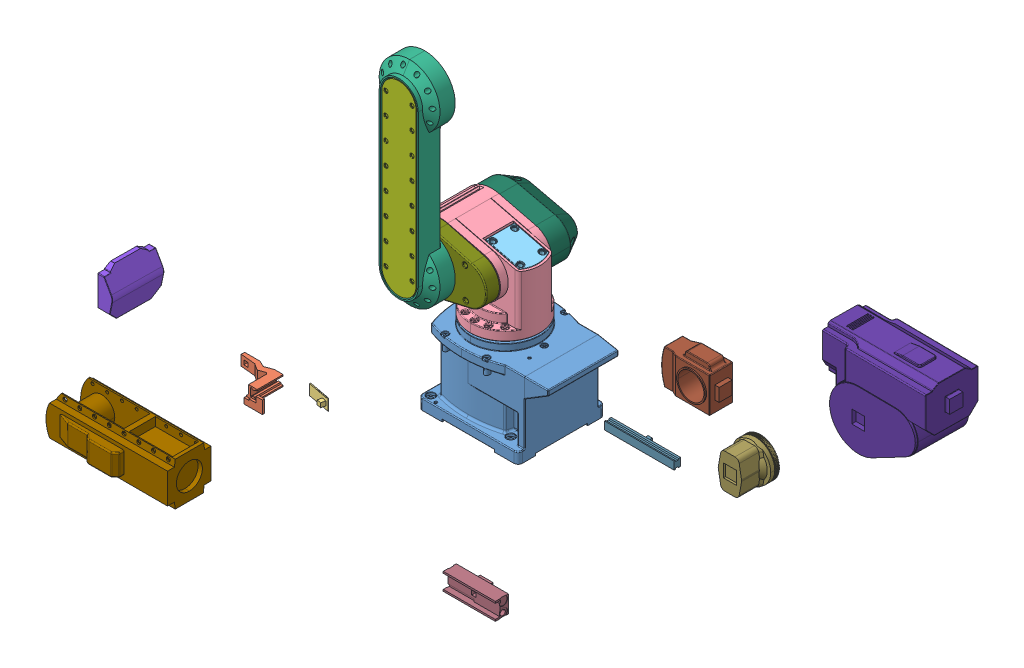
SolidWorks assembly Movable Step asembly, configuration Default. Lengths in mm.
Overall size (1391.39 998.07 787.43).
17 component instances, 17 part files, 19 mates.
Components (placement in the parent):
- Base.step-1: Base.step [Default] at (50.8691 16.3662 238.0648) size (280 185 200)
- Gripper_left^industry_robot_arm_3.step-1: Gripper_left^industry_robot_arm_3.step [Default] at (673.7931 -125.95 576.646) size (105.79 39 65)
- Gripper_right_grip^industry_robot_arm_3.step-1: Gripper_right_grip^industry_robot_arm_3.step [Default] at (-1508.2384 -488.0095 2246.7024) size (52.87 24 20.92)
- Joint_1.step-1: Joint_1.step [Default] at (68.6257 327.9173 238.0648) size (242.75 189 160)
- Joint_1_top_cap.step-1: Joint_1_top_cap.step [Default] at (70.9238 311.3662 238.0648) x (1 0 0) z (0 1 0) size (91.2 70 52.34)
- Joint_2.step-1: Joint_2.step [Default] at (-21.3577 641.8554 242.1795) x (0 -0.999953 -0.009698) z (0.003009 -0.009698 0.999948) size (490.3 140.11 64.56)
- joint_2_cap.step-1: joint_2_cap.step [Default] at (-275.4813 138.7561 238.0648) x (0.296333 -0.955031 -0.010154) z (0.003009 -0.009698 0.999948) size (415.27 184.72 18.75)
- Joint_3_cap^industry_robot_arm_3.step-1: Joint_3_cap^industry_robot_arm_3.step [Default] at (-272.5519 -379.9218 510.6034) size (35.03 98 118.33)
- Joint_3_front^industry_robot_arm_3.step-1: Joint_3_front^industry_robot_arm_3.step [Default] at (-415.1839 -222.0873 595.2465) size (280 99.67 120)
- Joint_3_top_cap^industry_robot_arm_3.step-1: Joint_3_top_cap^industry_robot_arm_3.step [Default] at (442.8994 -263.6776 221.6348) size (97 20 57)
- joint_4^industry_robot_arm_3.step-1: joint_4^industry_robot_arm_3.step [Default] at (649.134 88.8541 95.9617) size (126.86 92 60)
- joint_4_front^industry_robot_arm_3.step-1: joint_4_front^industry_robot_arm_3.step [Default] at (660.0002 4.3894 125.0533) size (88 89.06 70)
- joint_4_super_front^industry_robot_arm_3.step-1: joint_4_super_front^industry_robot_arm_3.step [Default] at (-213.5534 -329.8265 362.4092) size (120 40 40)
- joint_4_super_front_middle^industry_robot_arm_3.step-1: joint_4_super_front_middle^industry_robot_arm_3.step [Default] at (-53.4809 -9.2536 206.8606) size (160 18 25)
- Part3.step-1: Part3.step [Default] at (73.4245 16.4054 238.0648) x (0.999815 0.016322 -0.010154) z (0.010153 0.000166 0.999948) size (205.53 137 83.39)
- Part4.step-1: Part4.step [Default] at (63.8269 16.4054 238.0648) x (0.999815 -0.016322 -0.010154) z (0.010153 -0.000166 0.999948) size (205.37 137 45.97)
- Part5.step-1: Part5.step [Default] at (696.2706 134.3097 -57.1849) size (270.42 212 122.27)
Mates (geometry in assembly coordinates):
- Concentric1: concentric anti-aligned: cylinder of Base.step-1 through (68.6257 191.3662 238.0648) axis (0 1 0) radius 70; cylinder of Joint_1.step-1 through (68.6257 217.3662 238.0648) axis (0 -1 0) radius 69
- Coincident1: coincident anti-aligned: plane of Base.step-1 through (68.6257 191.3662 238.0648) normal (0 1 0); plane of Joint_1.step-1 through (68.6257 191.3662 238.0648) normal (0 -1 0)
- Parallel1: parallel aligned: plane of Base.step-1 through (198.6257 106.3662 323.0648) normal (0 0 1); plane of Joint_1.step-1 through (68.6257 327.9173 298.0648) normal (0 0 1)
- Coincident3: coincident anti-aligned: plane of Joint_1.step-1 through (68.6257 311.3662 238.0648) normal (0 1 0); plane of Joint_1_top_cap.step-1 through (70.9238 311.3662 238.0648) normal (0 -1 0)
- Concentric2: concentric aligned: cylinder of Joint_1.step-1 through (68.6257 380.3662 238.0648) axis (0 -1 0) radius 75; cylinder of Joint_1_top_cap.step-1 through (68.6257 465.158 238.0648) axis (0 -1 0) radius 75.4393
- Parallel2: parallel anti-aligned: plane of Joint_1.step-1 through (52.4208 380.3662 273.0648) normal (1 0 0); plane of Joint_1_top_cap.step-1 through (56.2189 465.158 204.5648) normal (-1 0 0)
- Coincident4: coincident anti-aligned: plane of Joint_1.step-1 through (68.6257 327.9173 178.0648) normal (0 0 -1); plane of Part3.step-1 through (68.6257 310.3662 178.0648) normal (0 0 1)
- Concentric3: concentric anti-aligned: cylinder of Joint_1.step-1 through (68.6257 310.3662 278.0648) axis (0 0 -1) radius 48.4134; cylinder of Part3.step-1 through (68.6257 310.3662 98.0648) axis (0 0 1) radius 46.9225
- Tangent1: tangent aligned: cylinder of Joint_1.step-1 through (-21.3697 310.3662 278.0648) axis (0 0 -1) radius 70; cylinder of Part3.step-1 through (-21.0421 308.9024 98.0648) axis (0 0 1) radius 68.5
- Concentric5: concentric aligned: cylinder of Joint_1.step-1 through (68.6257 310.3662 278.0648) axis (0 0 -1) radius 48.4134; cylinder of Part4.step-1 through (68.6257 310.3662 328.0648) axis (0 0 -1) radius 46.9225
- Coincident5: coincident anti-aligned: plane of Joint_1.step-1 through (68.6257 327.9173 298.0648) normal (0 0 1); plane of Part4.step-1 through (68.6257 310.3662 298.0648) normal (0 0 -1)
- Tangent2: tangent aligned: cylinder of Joint_1.step-1 through (-21.3697 310.3662 278.0648) axis (0 0 -1) radius 70; cylinder of Part4.step-1 through (-21.0421 311.83 328.0648) axis (0 0 -1) radius 68.5
- Coincident6: coincident anti-aligned: plane of Joint_2.step-1 through (-102.3943 333.8552 230.5188) normal (0 0 1); plane of joint_2_cap.step-1 through (-21.3577 311.8352 378.0648) normal (0 0 -1)
- Concentric8: concentric anti-aligned: cylinder of Joint_2.step-1 through (-21.3577 -6.6174 230.5188) axis (0 0 1) radius 42; cylinder of joint_2_cap.step-1 through (-21.3577 311.8352 392.6048) axis (0 0 -1) radius 39.5
- Concentric9: concentric anti-aligned: cylinder of Joint_2.step-1 through (-102.3943 333.8552 230.5188) axis (0 0 1) radius 42; cylinder of joint_2_cap.step-1 through (-102.3943 652.3077 392.6048) axis (0 0 -1) radius 39.5
- Coincident7: coincident anti-aligned: plane of Joint_2.step-1 through (-21.3577 -6.6174 185.5188) normal (0 0 -1); plane of Part4.step-1 through (-21.3577 311.8352 333.0648) normal (0 0 1)
- Coincident10: coincident anti-aligned: plane of Joint_2.step-1 through (-21.3577 -6.6174 185.5188) normal (0 0 -1); plane of Part4.step-1 through (-21.3577 311.8352 333.0648) normal (0 0 1)
- Concentric13: concentric aligned: cylinder of Joint_2.step-1 through (-21.3577 -6.6174 195.5188) axis (0 0 -1) radius 30; cylinder of Part4.step-1 through (-21.3577 311.8352 343.0648) axis (0 0 -1) radius 30
- Parallel4: parallel aligned: plane of Base.step-1 through (198.6257 41.3662 138.0648) normal (1 0 0); plane of Joint_2.step-1
